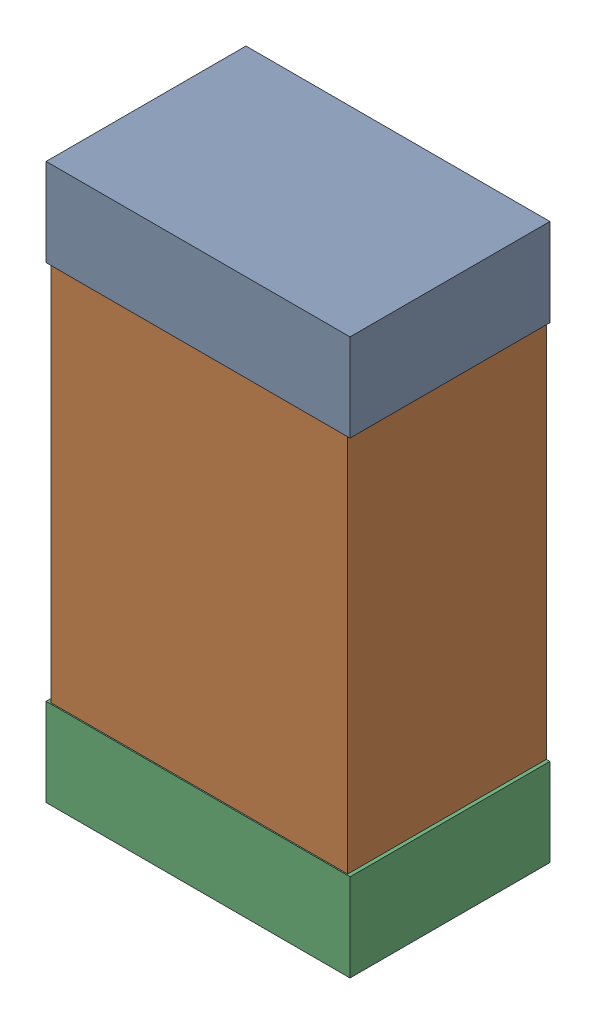
SolidWorks assembly 1MKanaloa_v2.0.0_Power, configuration Default. Lengths in mm.
Overall size (1.3 2.38 0.85).
6 component instances, 2 part files, 0 mates.
Components (placement in the parent):
- 330415056-1: 330415056 [Default] at (129.3608 91.5744 0) size (1.3 0.38 0.85)
  - Extruded_2-1: Extruded_2 [Default] at origin size (1.3 0.38 0.85)
- 334787376-1: 334787376 [Default] at (129.3608 90.5744 0) size (1.27 2.2 0.85)
  - Extruded_16-1: Extruded_16 [Default] at origin size (1.27 2.2 0.85)
- 330415056-2: 330415056 [Default] at (129.3608 89.5744 0) size (1.3 0.38 0.85)
  - Extruded_2-1: Extruded_2 [Default] at origin size (1.3 0.38 0.85)
